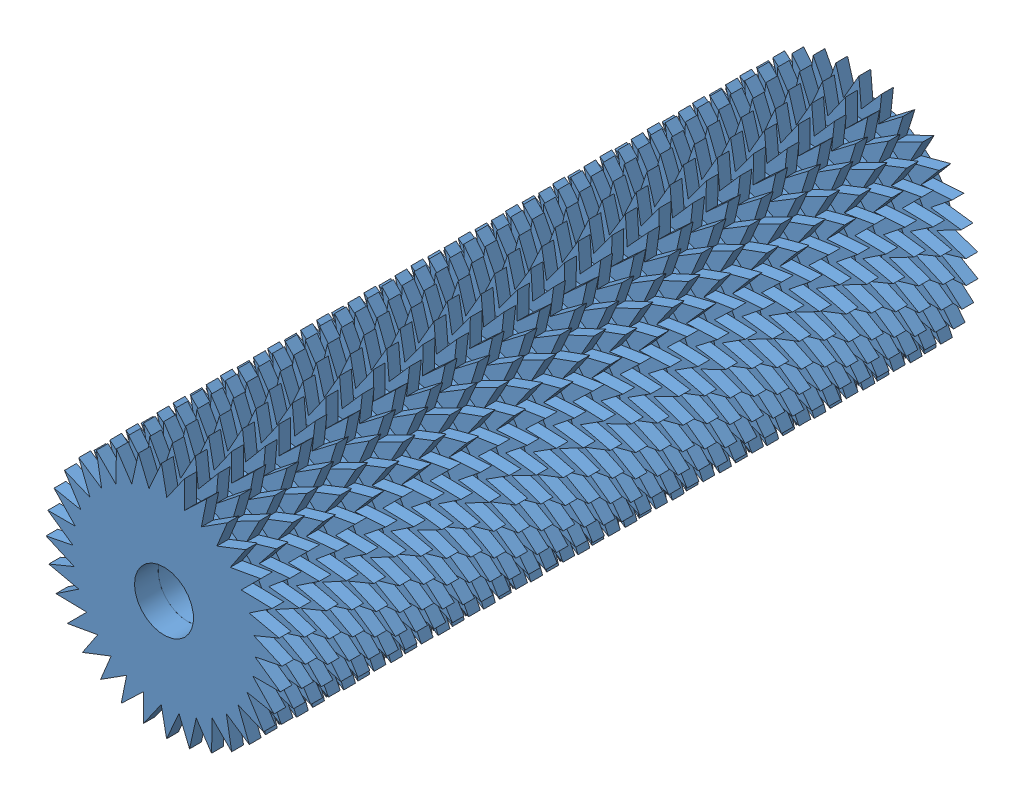
SolidWorks assembly uzun_silindir, configuration Varsayılan. Lengths in mm.
Overall size (29.16 29.16 60).
36 component instances, 1 part files, 20 mates.
Components (placement in the parent):
- kısa_sılındır-1: kısa_sılındır [Varsayılan] at (-17.2962 -1.6546 23.1558) size (23.52 23.52 10)
  - Parça1-3: Parça1 [Varsayılan] at (13.9957 5.0507 15.6098) size (20 20 2)
  - Parça1-4: Parça1 [Varsayılan] at (13.9957 5.0507 11.6098) x (0.980785 0.19509 0) z (0 0 1) size (20 20 2)
  - Parça1-5: Parça1 [Varsayılan] at (13.9957 5.0507 13.6098) x (0.994056 0.108867 0) z (0 0 1) size (20 20 2)
  - Parça1-6: Parça1 [Varsayılan] at (13.9957 5.0507 17.6098) x (0.996195 -0.087156 0) z (0 0 1) size (20 20 2)
  - Parça1-7: Parça1 [Varsayılan] at (13.9957 5.0507 19.6098) x (0.980785 -0.19509 0) z (0 0 1) size (20 20 2)
- kısa_sılındır-2: kısa_sılındır [Varsayılan] at (-16.6632 -3.1482 33.1558) x (0.994056 0.108867 0) z (0 0 1) size (23.52 23.52 10)
  - Parça1-3: Parça1 [Varsayılan] at (13.9957 5.0507 15.6098) size (20 20 2)
  - Parça1-4: Parça1 [Varsayılan] at (13.9957 5.0507 11.6098) x (0.980785 0.19509 0) z (0 0 1) size (20 20 2)
  - Parça1-5: Parça1 [Varsayılan] at (13.9957 5.0507 13.6098) x (0.994056 0.108867 0) z (0 0 1) size (20 20 2)
  - Parça1-6: Parça1 [Varsayılan] at (13.9957 5.0507 17.6098) x (0.996195 -0.087156 0) z (0 0 1) size (20 20 2)
  - Parça1-7: Parça1 [Varsayılan] at (13.9957 5.0507 19.6098) x (0.980785 -0.19509 0) z (0 0 1) size (20 20 2)
- kısa_sılındır-3: kısa_sılındır [Varsayılan] at (-15.8713 -4.5641 43.1558) x (0.976296 0.21644 0) z (0 0 1) size (23.52 23.52 10)
  - Parça1-3: Parça1 [Varsayılan] at (13.9957 5.0507 15.6098) size (20 20 2)
  - Parça1-4: Parça1 [Varsayılan] at (13.9957 5.0507 11.6098) x (0.980785 0.19509 0) z (0 0 1) size (20 20 2)
  - Parça1-5: Parça1 [Varsayılan] at (13.9957 5.0507 13.6098) x (0.994056 0.108867 0) z (0 0 1) size (20 20 2)
  - Parça1-6: Parça1 [Varsayılan] at (13.9957 5.0507 17.6098) x (0.996195 -0.087156 0) z (0 0 1) size (20 20 2)
  - Parça1-7: Parça1 [Varsayılan] at (13.9957 5.0507 19.6098) x (0.980785 -0.19509 0) z (0 0 1) size (20 20 2)
- kısa_sılındır-4: kısa_sılındır [Varsayılan] at (-15.3237 -5.3692 13.1558) x (0.96005 0.279829 0) z (0 0 1) size (23.52 23.52 10)
  - Parça1-3: Parça1 [Varsayılan] at (13.9957 5.0507 15.6098) size (20 20 2)
  - Parça1-4: Parça1 [Varsayılan] at (13.9957 5.0507 11.6098) x (0.980785 0.19509 0) z (0 0 1) size (20 20 2)
  - Parça1-5: Parça1 [Varsayılan] at (13.9957 5.0507 13.6098) x (0.994056 0.108867 0) z (0 0 1) size (20 20 2)
  - Parça1-6: Parça1 [Varsayılan] at (13.9957 5.0507 17.6098) x (0.996195 -0.087156 0) z (0 0 1) size (20 20 2)
  - Parça1-7: Parça1 [Varsayılan] at (13.9957 5.0507 19.6098) x (0.980785 -0.19509 0) z (0 0 1) size (20 20 2)
- kısa_sılındır-5: kısa_sılındır [Varsayılan] at (-18.0126 1.1729 3.1558) x (0.980785 -0.19509 0) z (0 0 1) size (23.52 23.52 10)
  - Parça1-3: Parça1 [Varsayılan] at (13.9957 5.0507 15.6098) size (20 20 2)
  - Parça1-4: Parça1 [Varsayılan] at (13.9957 5.0507 11.6098) x (0.980785 0.19509 0) z (0 0 1) size (20 20 2)
  - Parça1-5: Parça1 [Varsayılan] at (13.9957 5.0507 13.6098) x (0.994056 0.108867 0) z (0 0 1) size (20 20 2)
  - Parça1-6: Parça1 [Varsayılan] at (13.9957 5.0507 17.6098) x (0.996195 -0.087156 0) z (0 0 1) size (20 20 2)
  - Parça1-7: Parça1 [Varsayılan] at (13.9957 5.0507 19.6098) x (0.980785 -0.19509 0) z (0 0 1) size (20 20 2)
- kısa_sılındır-6: kısa_sılındır [Varsayılan] at (-17.6831 -0.4155 -6.8442) x (0.996195 -0.087156 0) z (0 0 1) size (23.52 23.52 10)
  - Parça1-3: Parça1 [Varsayılan] at (13.9957 5.0507 15.6098) size (20 20 2)
  - Parça1-4: Parça1 [Varsayılan] at (13.9957 5.0507 11.6098) x (0.980785 0.19509 0) z (0 0 1) size (20 20 2)
  - Parça1-5: Parça1 [Varsayılan] at (13.9957 5.0507 13.6098) x (0.994056 0.108867 0) z (0 0 1) size (20 20 2)
  - Parça1-6: Parça1 [Varsayılan] at (13.9957 5.0507 17.6098) x (0.996195 -0.087156 0) z (0 0 1) size (20 20 2)
  - Parça1-7: Parça1 [Varsayılan] at (13.9957 5.0507 19.6098) x (0.980785 -0.19509 0) z (0 0 1) size (20 20 2)
Mates (geometry in assembly coordinates):
- Eş Merkezli1: concentric: kısa_sılındır-1, kısa_sılındır-2
- Eş Merkezli2: concentric: kısa_sılındır-2, kısa_sılındır-3
- Eş Merkezli3: concentric: kısa_sılındır-1, kısa_sılındır-4
- Eş Merkezli4: concentric: kısa_sılındır-4, kısa_sılındır-5
- Eş Merkezli5: concentric: kısa_sılındır-5, kısa_sılındır-6
- Açı1: planar angle: kısa_sılındır-6, kısa_sılındır-5
- Çakışık3: coincident: kısa_sılındır-5, kısa_sılındır-6
- Açı2: planar angle: kısa_sılındır-5, kısa_sılındır-4
- Çakışık5: coincident: kısa_sılındır-4, kısa_sılındır-5
- Açı3: planar angle: kısa_sılındır-1, kısa_sılındır-4
- Çakışık7: coincident: kısa_sılındır-1, kısa_sılındır-4
- Açı4: planar angle: kısa_sılındır-2, kısa_sılındır-1
- Çakışık9: coincident: kısa_sılındır-1, kısa_sılındır-2
- Açı5: planar angle: kısa_sılındır-3, kısa_sılındır-2
- Çakışık11: coincident: kısa_sılındır-2, kısa_sılındır-3
- Eş Merkezli1: concentric: 
- Uzaklık1: distance: 
- Teğet1: tangent: 
- Teğet2: tangent: 
- GearMate1: gear: 
